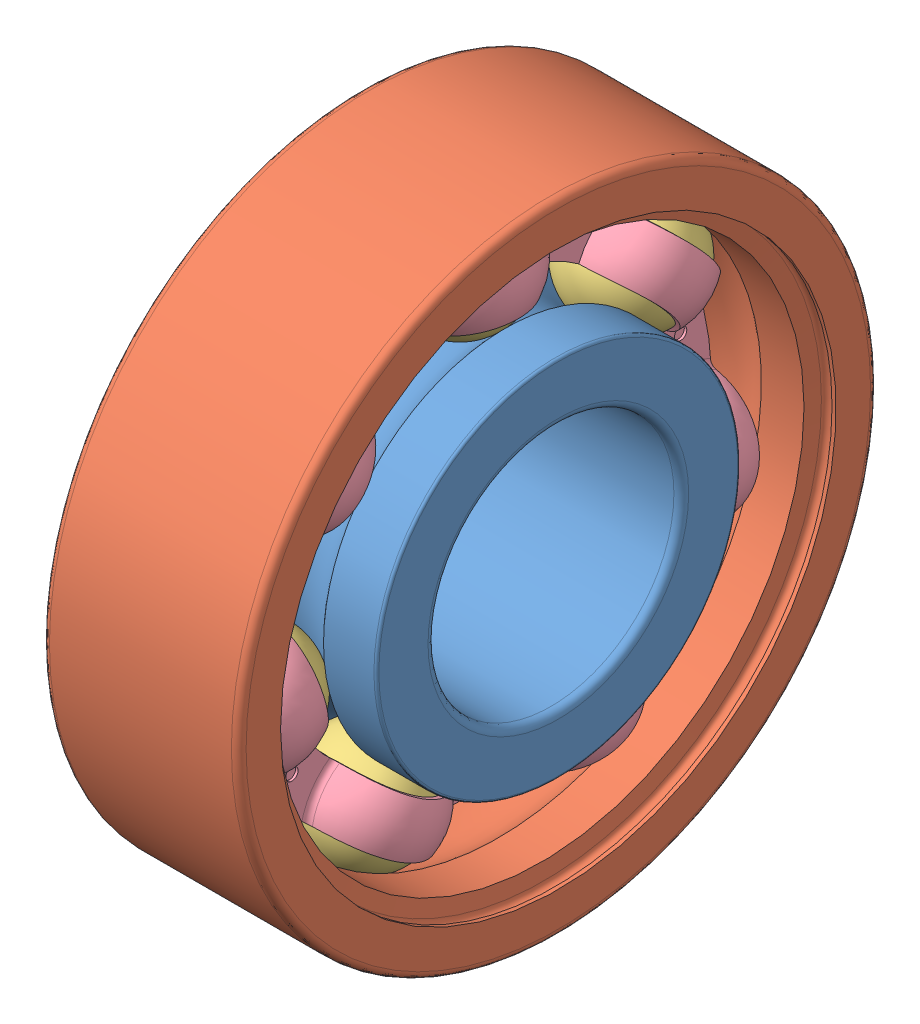
SolidWorks assembly 6000 - bearing, configuration Default. Lengths in mm.
Overall size (8 26 26).
11 component instances, 4 part files, 12 mates.
Components (placement in the parent):
- 6000 - core-1: 6000 - core [Default] at origin size (8 14.8 14.8)
- 6000 - outer-1: 6000 - outer [Default] x (0 0 1) z (-1 0 0) size (26 26 8)
- 6000 - ball-1: 6000 - ball [Default] at (4 0 0) size (4.76 4.76 4.76)
- 6000 - ball-2: 6000 - ball [Default] at (4 0 0) x (1 0 0) z (0 -0.781831 0.62349) size (4.76 4.76 4.76)
- 6000 - ball-3: 6000 - ball [Default] at (4 0 0) x (1 0 0) z (0 -0.974928 -0.222521) size (4.76 4.76 4.76)
- 6000 - ball-4: 6000 - ball [Default] at (4 0 0) x (1 0 0) z (0 -0.433884 -0.900969) size (4.76 4.76 4.76)
- 6000 - ball-5: 6000 - ball [Default] at (4 0 0) x (1 0 0) z (0 0.433884 -0.900969) size (4.76 4.76 4.76)
- 6000 - ball-6: 6000 - ball [Default] at (4 0 0) x (1 0 0) z (0 0.974928 -0.222521) size (4.76 4.76 4.76)
- 6000 - ball-7: 6000 - ball [Default] at (4 0 0) x (1 0 0) z (0 0.781831 0.62349) size (4.76 4.76 4.76)
- 6000 - cage-1: 6000 - cage [Default] at (4 0 0) x (0 0 -1) z (1 0 0) size (20 20 2.62)
- 6000 - cage-2: 6000 - cage [Default] at (4 0 0.0072) x (0 0 1) z (-1 0 0) size (20 20 2.62)
Mates (geometry in assembly coordinates):
- Coincident2: coincident aligned: plane of 6000 - core-1 through (0 0 0) normal (0 0 1); plane of assembly through (0 0 0) normal (0 0 1)
- Coincident3: coincident aligned: plane of 6000 - core-1 through (0 0 0) normal (0 1 0); plane of assembly through (0 0 0) normal (0 1 0)
- Coincident4: coincident aligned: plane of 6000 - core-1 through (0 0 0) normal (1 0 0); plane of assembly through (0 0 0) normal (1 0 0)
- Coincident5: coincident aligned: plane of 6000 - outer-1 through (0 0 0) normal (0 0 1); plane of assembly through (0 0 0) normal (0 0 1)
- Coincident6: coincident anti-aligned: plane of 6000 - outer-1 through (0 0 0) normal (-1 0 0); plane of assembly through (0 0 0) normal (1 0 0)
- Coincident7: coincident aligned: plane of 6000 - outer-1; plane of assembly through (0 0 0) normal (0 1 0)
- Coincident8: coincident aligned: plane of 6000 - ball-1 through (4 0 0) normal (0 1 0); plane of assembly through (0 0 0) normal (0 1 0)
- Coincident9: coincident aligned: plane of 6000 - ball-1 through (4 0 0) normal (0 0 1); plane of assembly through (0 0 0) normal (0 0 1)
- Distance1: distance = 4 mm aligned: plane of 6000 - ball-1 through (4 0 0) normal (1 0 0); plane of assembly through (0 0 0) normal (1 0 0)
- Distance2: distance = 4 mm aligned: plane of 6000 - cage-1 through (4 0 0) normal (1 0 0); plane of assembly through (0 0 0) normal (1 0 0)
- Coincident12: coincident aligned: plane of 6000 - cage-1; plane of assembly through (0 0 0) normal (0 1 0)
- Coincident13: coincident anti-aligned: plane of 6000 - cage-1 through (4 0 0) normal (0 0 -1); plane of assembly through (0 0 0) normal (0 0 1)
